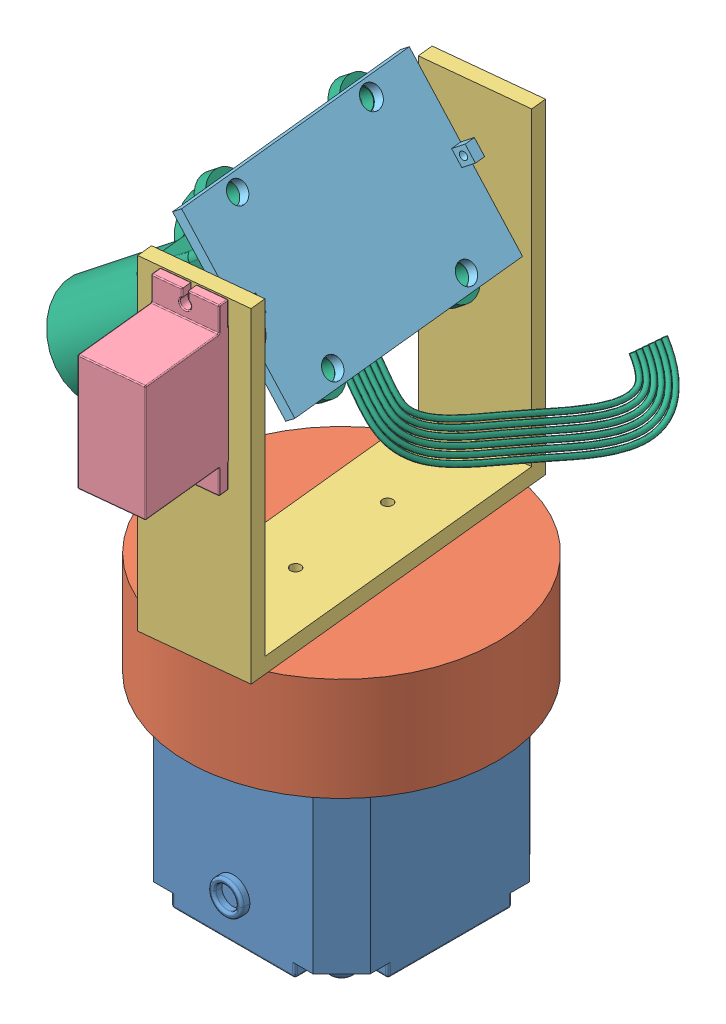
SolidWorks assembly Assem4, configuration Default. Lengths in mm.
Overall size (106.35 174.27 86.65).
7 component instances, 6 part files, 0 mates.
Components (placement in the parent):
- new assem-1: new assem [Default] at (40.772 16.69 98.6379) size (85.98 121.11 106.78)
  - stepper motor from datasheet-2: stepper motor from datasheet [Default] at (-5.9351 40.0569 49.5075) x (-1 0 0) z (0 1 0) size (42.06 43.63 53.04)
  - gear-1: gear [Default] at (-5.9351 62.0569 49.5075) x (0.10359 0 0.99462) z (0 -1 0) size (60 60 20)
  - uclamp-1: uclamp [Default] at (-18.8854 65.0569 21.6994) x (0.10359 0 0.99462) z (-0.99462 0 0.10359) size (64 63 20)
  - ServoMotor-1: ServoMotor [Default] at (-2.4131 108.8569 83.3246) x (0 -1 0) z (0.99462 0 -0.10359) size (32 29 12)
  - lidarbase-1: lidarbase [Default] at (-13.6193 117.0166 39.5253) x (-0.10359 0 -0.99462) z (0.791781 0.605213 -0.082464) size (49.5 33 5)
  - Lidar-Lite-V3-1: Lidar-Lite-V3 [Default] at (-11.0937 110.4372 46.29) x (-0.102855 -0.000971 -0.994696) z (-0.602083 0.796063 0.061481) size (74.48 42.89 67.86)
